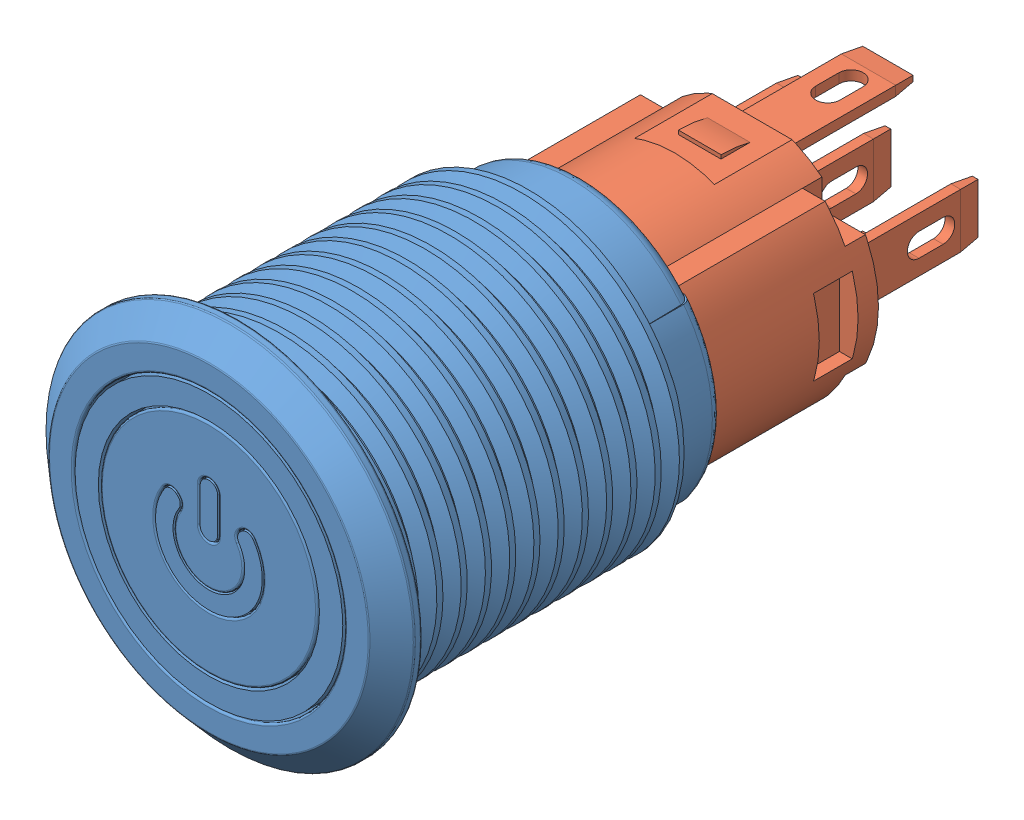
SolidWorks assembly 16mm-LED-Power-Button, configuration Default. Lengths in mm.
Overall size (19 19 35).
3 component instances, 3 part files, 2 mates.
Components (placement in the parent):
- Button_Body-1: Button_Body [Default] at origin size (19 19 19.3)
- Socket-1: Socket [Default] at origin size (12.92 12.92 26)
- Hex_Nut_M16-3mm-2: Hex_Nut_M16-3mm [Default] at (0 0 4.5) size (19 21.94 3.41) (hidden)
Mates (geometry in assembly coordinates):
- Concentric1: concentric anti-aligned: circle of Hex_Nut_M16-3mm-2; circle of Button_Body-1
- Coincident1: coincident anti-aligned: plane of Button_Body-1 through (0 0 7.5) normal (0 0 -1); plane of Hex_Nut_M16-3mm-2 through (0 0 7.5) normal (0 0 1)
